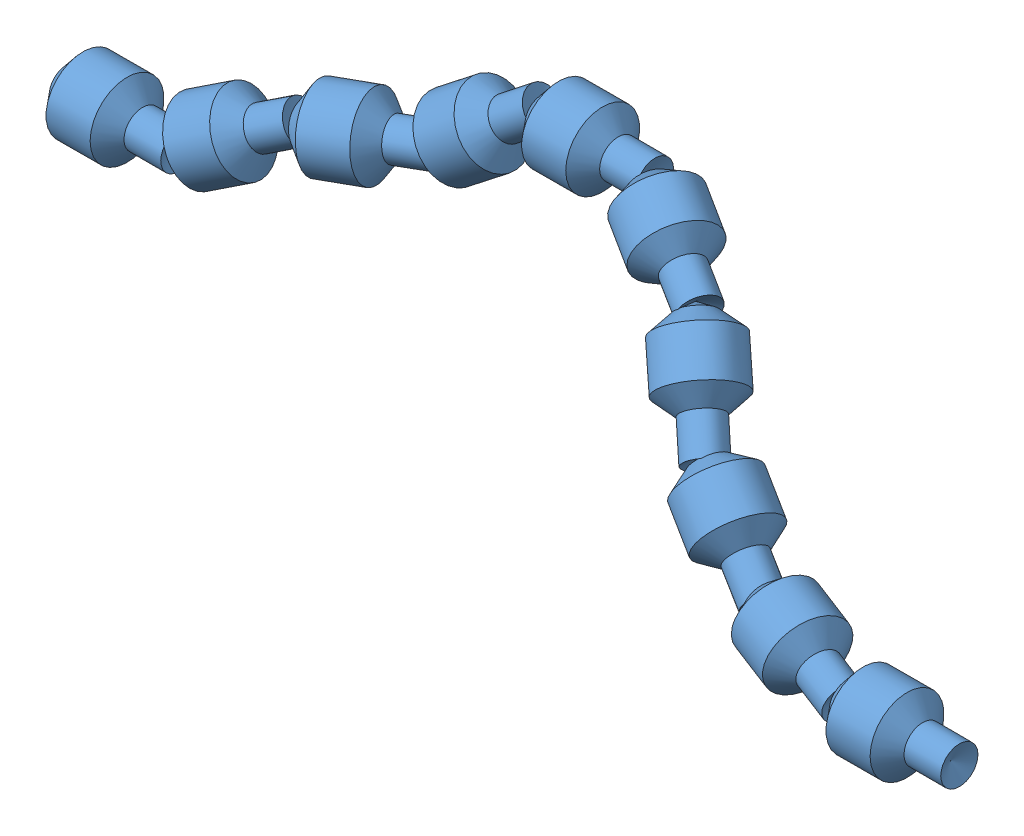
SolidWorks assembly Ensamblaje1, configuration Predeterminado. Lengths in mm.
Overall size (1342.22 373.25 344.49).
10 component instances, 1 part files, 9 mates.
Components (placement in the parent):
- Parte 1-1: Parte 1 [Predeterminado] at (90.056 -2.849 163.2626) size (163.26 99.83 99.83)
- Parte 1-2: Parte 1 [Predeterminado] at (-65.4664 -3.2796 166.1975) x (0.949353 -0.197041 0.244751) z (-0.212827 0.1698 0.962223) size (163.26 99.83 99.83)
- Parte 1-3: Parte 1 [Predeterminado] at (-215.223 27.2251 128.772) x (0.799727 -0.513311 0.311365) z (-0.215422 0.238742 0.946887) size (163.26 99.83 99.83)
- Parte 1-4: Parte 1 [Predeterminado] at (-690.004 259.37 -65.7055) x (0.791723 0.59444 -0.14077) z (0.294923 -0.17014 0.940251) size (163.26 99.83 99.83)
- Parte 1-5: Parte 1 [Predeterminado] at (-545.078 253.3616 -60.4412) size (163.26 99.83 99.83)
- Parte 1-6: Parte 1 [Predeterminado] at (-815.7128 164.1098 -42.6936) x (0.943977 0.156292 -0.290654) z (0.308977 -0.109167 0.944784) size (163.26 99.83 99.83)
- Parte 1-7: Parte 1 [Predeterminado] at (-424.0621 199.8298 4.8151) x (0.843511 -0.351488 0.406135) z (-0.32542 0.267124 0.907054) size (163.26 99.83 99.83)
- Parte 1-8: Parte 1 [Predeterminado] at (-340.9706 108.0099 83.8267) x (0.589871 -0.625348 0.510875) z (-0.196185 0.502724 0.841891) size (163.26 99.83 99.83)
- Parte 1-9: Parte 1 [Predeterminado] at (-1088.9045 65.5226 38.5999) size (163.26 99.83 99.83)
- Parte 1-10: Parte 1 [Predeterminado] at (-953.9679 143.602 3.5165) x (0.845487 0.486219 -0.220778) z (0.208628 0.079813 0.974733) size (163.26 99.83 99.83)
Mates (geometry in assembly coordinates):
- Coincidente2: coincident: point of Parte 1-1; point of Parte 1-2
- Coincidente3: coincident: point of Parte 1-2; point of Parte 1-3
- Coincidente4: coincident: point of Parte 1-3; point of Parte 1-8
- Coincidente5: coincident: point of Parte 1-7; point of Parte 1-8
- Coincidente6: coincident: point of Parte 1-5; point of Parte 1-7
- Coincidente7: coincident: point of Parte 1-4; point of Parte 1-5
- Coincidente8: coincident: point of Parte 1-4; point of Parte 1-6
- Coincidente9: coincident: point of Parte 1-6; point of Parte 1-10
- Coincidente10: coincident: point of Parte 1-9; point of Parte 1-10
